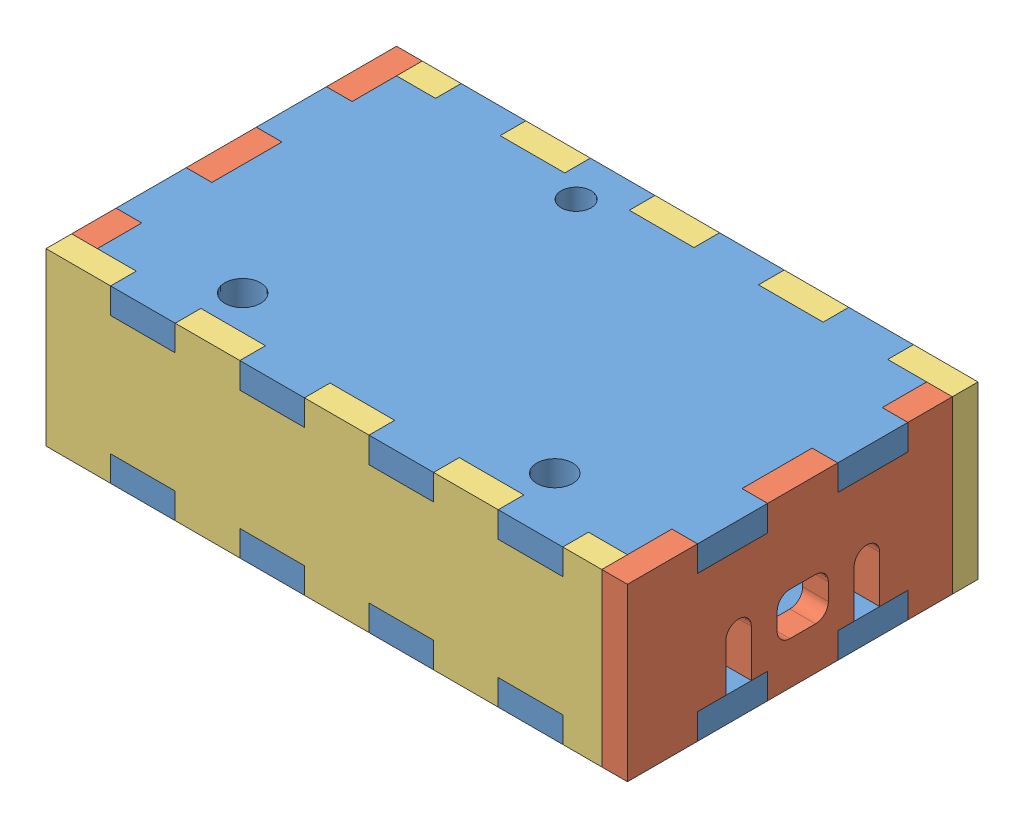
SolidWorks assembly DC-DC Boost LED, configuration Default. Lengths in mm.
Overall size (68 20 41).
6 component instances, 3 part files, 18 mates.
Components (placement in the parent):
- unten_oben-1: unten_oben [Default] at (-9.1679 54.5344 97.0759) size (68 3 41)
- rechts_links-1: rechts_links [rechts] at (58.833 74.5344 97.0759) x (0 0 -1) z (0 1 0) size (38 3 20)
- vorne_hinten-1: vorne_hinten [Vorne] at (-9.1679 74.5344 97.0759) x (1 0 0) z (0 1 0) size (65 3 20)
- unten_oben-3: unten_oben [Deckel] at (-9.1679 71.5344 97.0759) size (68 3 41)
- rechts_links-4: rechts_links [links] at (-9.1679 74.5344 56.0765) x (0 0 1) z (0 1 0) size (38 3 20)
- vorne_hinten-4: vorne_hinten [Default] at (58.833 74.5344 56.0765) x (-1 0 0) z (0 1 0) size (65 3 20)
Mates (geometry in assembly coordinates):
- Deckungsgleich12: coincident aligned: plane of unten_oben-1 through (-9.1679 54.5344 97.0759) normal (0 -1 0); plane of rechts_links-1 through (55.833 54.5344 80.6757) normal (0 -1 0)
- Deckungsgleich14: coincident aligned: plane of unten_oben-1 through (-9.1679 57.5344 89.4649) normal (-1 0 0); plane of ? through (-9.1679 123.5344 97.0097) normal (-1 0 0)
- Deckungsgleich17: coincident aligned: plane of unten_oben-1 through (-9.1679 54.5344 97.0759) normal (0 -1 0); plane of ? through (-9.1679 54.5344 51.737) normal (0 -1 0)
- Deckungsgleich19: coincident aligned: plane of unten_oben-1 through (-0.7135 57.5344 97.0097) normal (0 0 1); plane of ? through (-9.1679 62.2019 97.0097) normal (0 0 1)
- Deckungsgleich22: coincident aligned: plane of unten_oben-1 through (-9.1679 54.5344 97.0759) normal (0 -1 0); plane of vorne_hinten-1 through (21.054 54.5344 94.0759) normal (0 -1 0)
- Deckungsgleich32: coincident aligned: plane of rechts_links-4 through (-9.1679 74.5344 56.0765) normal (-1 0 0); plane of unten_oben-3 through (-9.1679 74.5344 80.6762) normal (-1 0 0)
- Deckungsgleich38: coincident aligned: plane of unten_oben-3 through (-1.6122 74.5344 56.0765) normal (0 0 -1); plane of rechts_links-4 through (-6.1679 74.5344 56.0765) normal (0 0 -1)
- Deckungsgleich39: coincident aligned: plane of unten_oben-3 through (-9.1679 74.5344 97.0759) normal (0 1 0); plane of rechts_links-4 through (-6.1679 74.5344 56.0765) normal (0 1 0)
- Deckungsgleich43: coincident aligned: plane of unten_oben-1 through (13.4996 57.5344 97.0759) normal (0 0 1); plane of vorne_hinten-1 through (-9.1679 74.5344 97.0759) normal (0 0 1)
- Deckungsgleich45: coincident aligned: plane of vorne_hinten-1 through (-9.1679 74.5344 97.0759) normal (0 0 1); plane of unten_oben-3 through (43.7212 74.5344 97.0759) normal (0 0 1)
- Deckungsgleich46: coincident aligned: plane of unten_oben-1 through (-9.1679 57.5344 80.6762) normal (-1 0 0); plane of rechts_links-4 through (-9.1679 74.5344 56.0765) normal (-1 0 0)
- Deckungsgleich47: coincident aligned: plane of unten_oben-1 through (-9.1679 54.5344 97.0759) normal (0 -1 0); plane of rechts_links-4 through (-6.1679 54.5344 88.8768) normal (0 -1 0)
- Deckungsgleich48: coincident aligned: plane of unten_oben-1 through (-1.6122 57.5344 56.0765) normal (0 0 -1); plane of vorne_hinten-4 through (58.833 74.5344 56.0765) normal (0 0 -1)
- Deckungsgleich49: coincident aligned: plane of unten_oben-1 through (-9.1679 54.5344 97.0759) normal (0 -1 0); plane of vorne_hinten-4 through (-1.6117 54.5344 59.0765) normal (0 -1 0)
- Deckungsgleich50: coincident anti-aligned: plane of rechts_links-4 through (-6.1679 74.5344 56.0765) normal (1 0 0); plane of vorne_hinten-4 through (-6.1679 74.5344 59.0765) normal (-1 0 0)
- Deckungsgleich51: coincident aligned: plane of unten_oben-1 through (58.833 57.5344 64.2759) normal (1 0 0); plane of rechts_links-1 through (58.833 74.5344 97.0759) normal (1 0 0)
- Deckungsgleich52: coincident anti-aligned: plane of rechts_links-1 through (55.833 74.5344 59.0765) normal (0 0 -1); plane of vorne_hinten-4 through (58.833 74.5344 59.0765) normal (0 0 1)
- Deckungsgleich53: coincident anti-aligned: plane of rechts_links-1 through (55.833 74.5344 97.0759) normal (-1 0 0); plane of vorne_hinten-1 through (55.833 74.5344 94.0759) normal (1 0 0)
